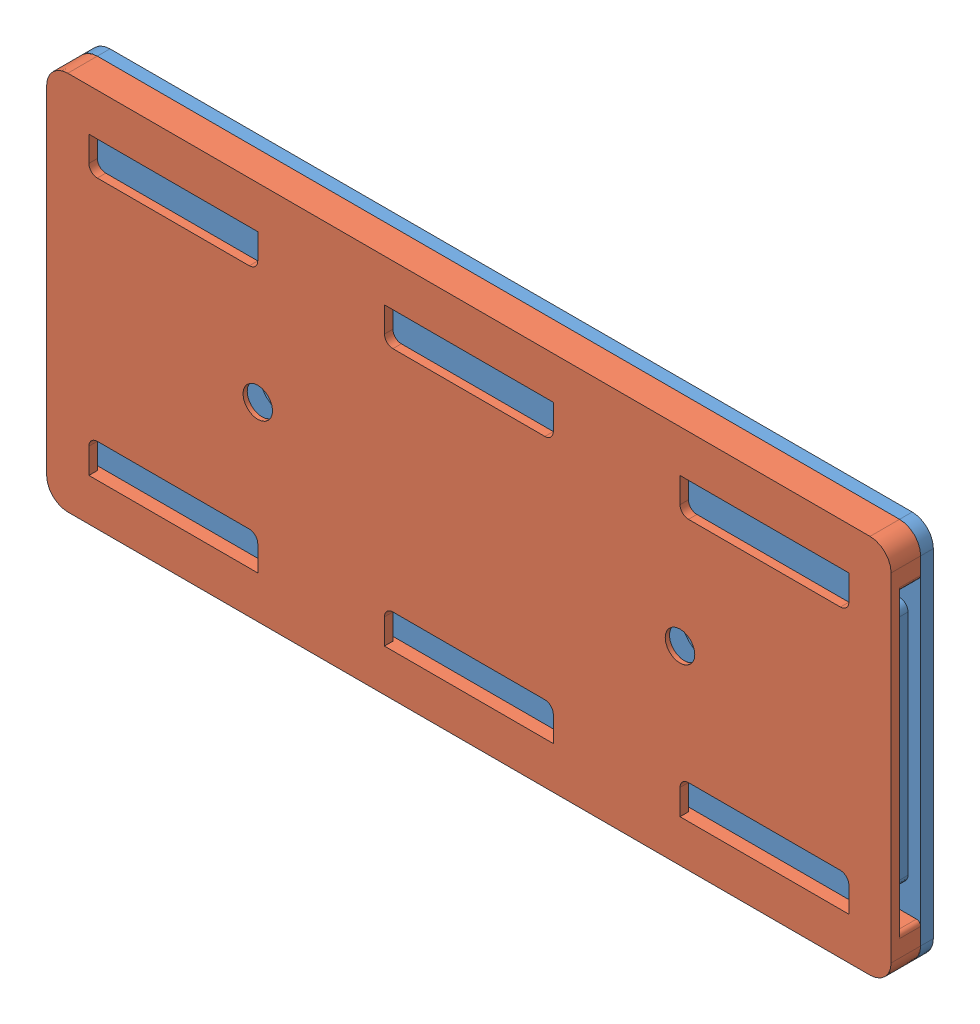
SolidWorks assembly Montagem1, configuration Valor predeterminado. Lengths in mm.
Overall size (100 45 5).
2 component instances, 2 part files, 2 mates.
Components (placement in the parent):
- suporte_filtro_top-1: suporte_filtro_top [Valor predeterminado] at (-120.1501 -9.4862 -2) size (100 45 4)
- suporte_filtro-1: suporte_filtro [Valor predeterminado] at (-120.1501 -9.4862 -0.5) x (-1 0 0) z (0 0 1) size (100 45 3.5)
Mates (geometry in assembly coordinates):
- Coincidente1: coincident anti-aligned: plane of suporte_filtro_top-1 through (-120.1501 -9.4862 -0.5) normal (0 0 1); plane of suporte_filtro-1 through (-120.1501 -9.4862 -0.5) normal (0 0 -1)
- Concêntrico1: concentric anti-aligned: circle of suporte_filtro_top-1; circle of suporte_filtro-1
